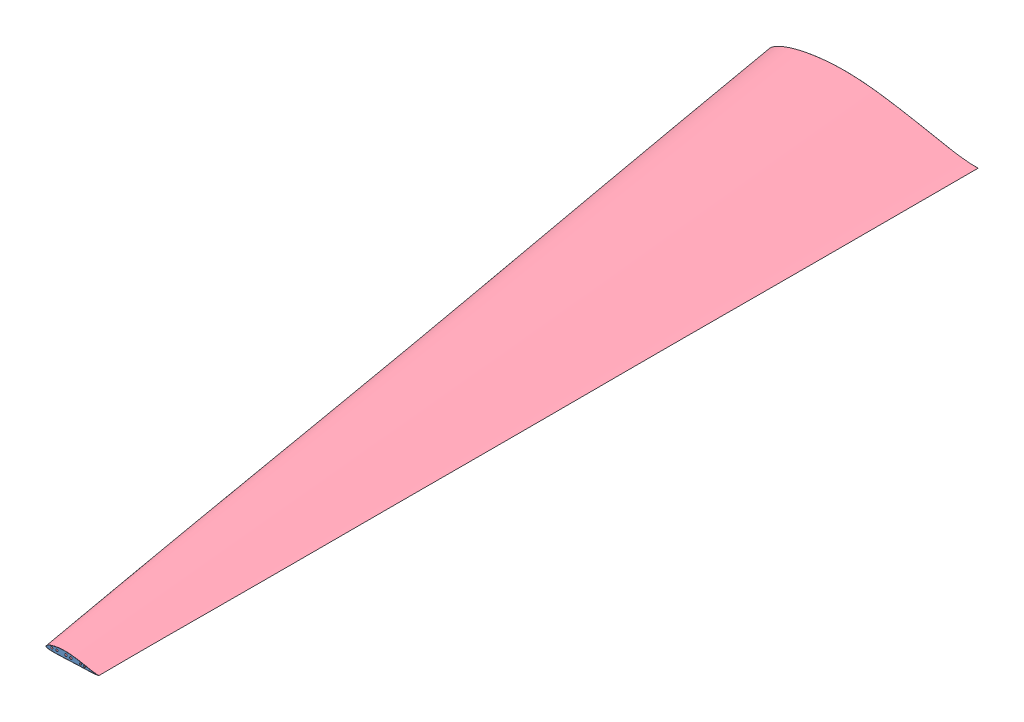
SolidWorks assembly Wing_Structure_Analysis.IGS, configuration Default. Lengths in mm.
Overall size (1986.38 492.87 7185.8).
4 component instances, 4 part files, 1 mates.
Components (placement in the parent):
- Analysis_Structure-2: Analysis_Structure [Default] at origin size (1708.54 215.45 7101)
- Section_Surface-4: Section_Surface [Default] at (-606.4856 13.2492 -1675.3635) x (0.997431 0.044916 -0.055804) z (0.056292 -0.009665 0.998368) size (545.38 96.46 7142.99)
- Section_Surface2-1: Section_Surface2 [Default] at (2.9132 0.0685 -1774) size (545.38 96.46 7100)
- Wing_Surface-1: Wing_Surface [Default] at (-0.0324 -0.1951 -1774) size (1986.38 492.87 7185.8)
Mates (geometry in assembly coordinates):
- Tangent4: tangent: curve of Analysis_Structure-2; curve of Wing_Surface-1
